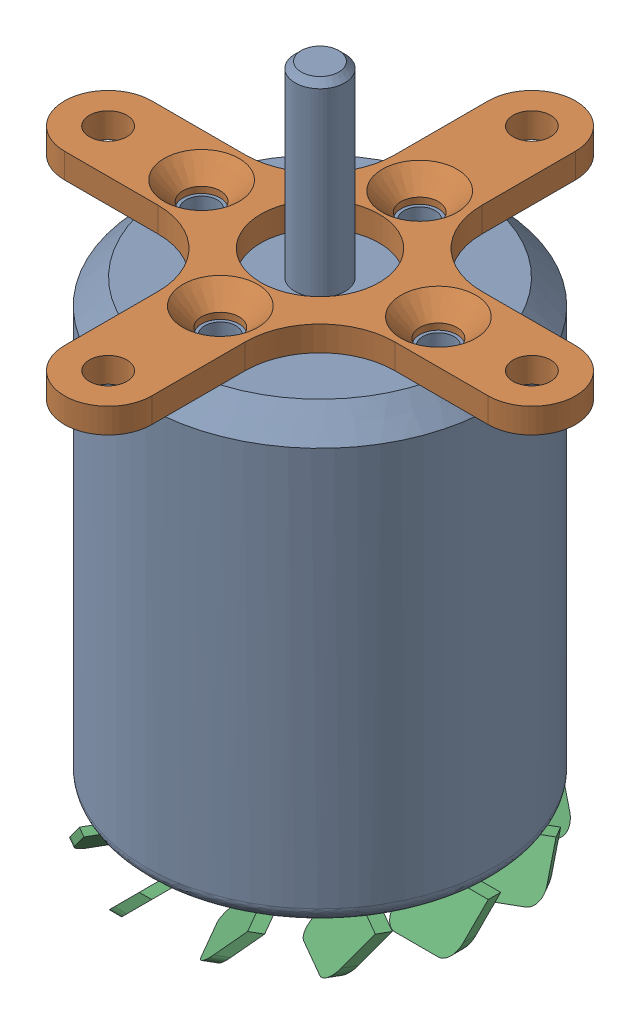
SolidWorks assembly Brushless Motor Assembly, configuration Default. Lengths in mm.
Overall size (41 54 41).
3 component instances, 3 part files, 7 mates.
Components (placement in the parent):
- D2836EVO Brushless Motor-1: D2836EVO Brushless Motor [Default] at origin size (28.58 53 28.58)
- Brushless Motor Mount-1: Brushless Motor Mount [Default] at origin size (41 2 41)
- Weapon Motor Fan-1: Weapon Motor Fan [Default] at (0 -36 0) x (1 0 0) z (0 -1 0) size (28 28 3)
Mates (geometry in assembly coordinates):
- Concentric1: concentric aligned: cylinder of D2836EVO Brushless Motor-1 through (0 15 0) axis (0 -1 0) radius 2; cylinder of Brushless Motor Mount-1 through (0 2 0) axis (0 -1 0) radius 4.75
- Coincident1: coincident anti-aligned: plane of D2836EVO Brushless Motor-1 through (0 0 0) normal (0 1 0); plane of Brushless Motor Mount-1 through (0 0 17) normal (0 -1 0)
- Concentric2: concentric anti-aligned: cylinder of D2836EVO Brushless Motor-1 through (0 0 8) axis (0 1 0) radius 1.25; cylinder of Brushless Motor Mount-1 through (0 2 8) axis (0 -1 0) radius 1.5
- Coincident3: coordinate: point of Brushless Motor Mount-1
- Concentric4: concentric aligned: cylinder of D2836EVO Brushless Motor-1 through (0 -38 0) axis (0 1 0) radius 2; cylinder of Weapon Motor Fan-1 through (0 -38 0) axis (0 1 0) radius 2.5
- Concentric5: concentric aligned: cylinder of D2836EVO Brushless Motor-1 through (6 -36 0) axis (0 -1 0) radius 1.25; cylinder of Weapon Motor Fan-1 through (6 -38 0) axis (0 -1 0) radius 1.6
- Coincident6: coincident anti-aligned: plane of D2836EVO Brushless Motor-1 through (0 -36 0) normal (0 -1 0); plane of Weapon Motor Fan-1 through (0 -36 0) normal (0 1 0)
